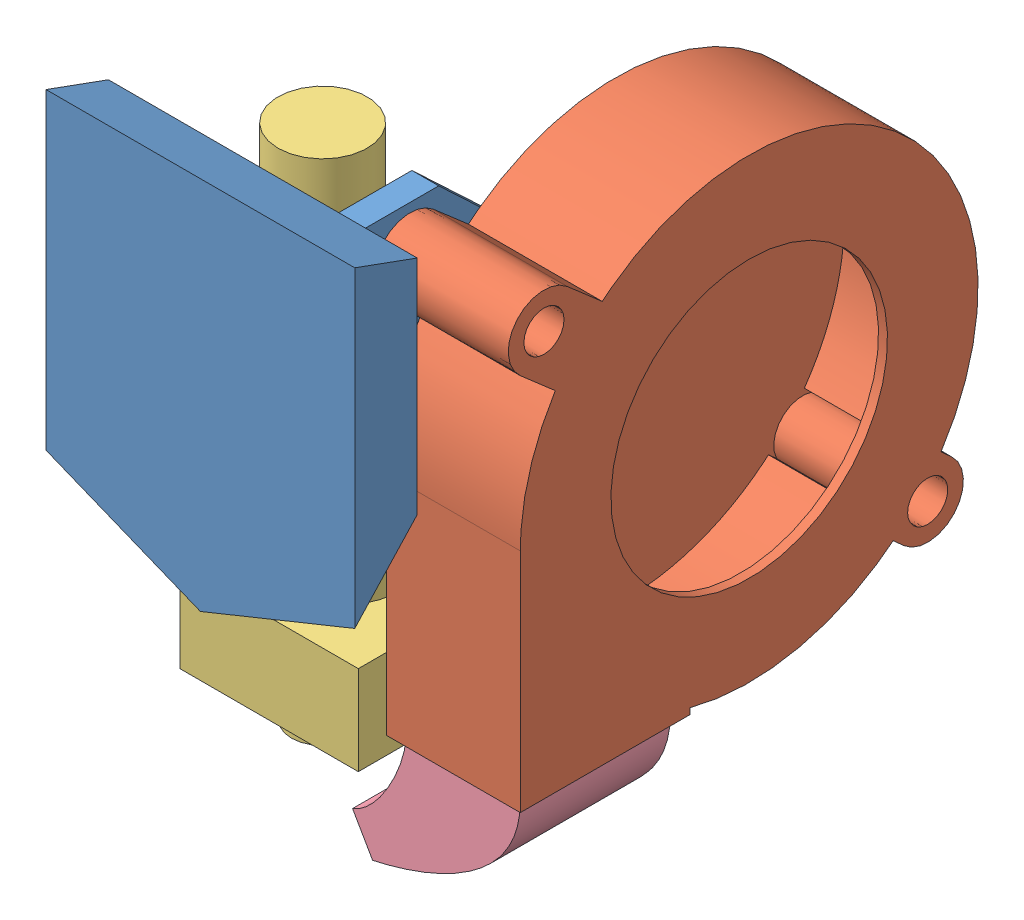
SolidWorks assembly Printer tool CR10, configuration Valor predeterminado. Lengths in mm.
Overall size (50 68.9 61).
4 component instances, 4 part files, 9 mates.
Components (placement in the parent):
- Printer_tool_CR10-1: Printer_tool_CR10 [Valor predeterminado] at (-2.4776 10.2101 60.4619) size (40.8 62.55 59)
- Cooler (50x50x15)-1: Cooler (50x50x15) [Valor predeterminado] at (9.0224 0.1623 25.4619) x (0 1 0) z (1 0 0) size (51.8 53 15)
- cr10_hotend-1: cr10_hotend [Valor predeterminado] at (-9.9776 -7.1878 39.2619) size (20 60 20.15)
- fan_duct-1: fan_duct [Valor predeterminado] at (16.5224 -10.2377 41.6119) x (0 0 -1) z (0 -1 0) size (36.4 19.53 29.42)
Mates (geometry in assembly coordinates):
- Concêntrico1: concentric aligned: cylinder of Printer_tool_CR10-1 through (9.0224 20.1623 48.4619) axis (-1 0 0) radius 2; cylinder of Cooler (50x50x15)-1 through (24.0224 20.1623 48.4619) axis (-1 0 0) radius 2.25
- Concêntrico2: concentric aligned: cylinder of Printer_tool_CR10-1 through (9.0224 -17.8377 5.4619) axis (-1 0 0) radius 2; cylinder of Cooler (50x50x15)-1 through (24.0224 -17.8377 5.4619) axis (-1 0 0) radius 2.25
- Coincidente1: coincident anti-aligned: plane of Printer_tool_CR10-1 through (9.0224 -17.8377 5.4619) normal (1 0 0); plane of Cooler (50x50x15)-1 through (9.0224 0.1623 25.4619) normal (-1 0 0)
- Concêntrico3: concentric aligned: cylinder of Printer_tool_CR10-1 through (-2.9776 2.8122 50.2619) axis (0 0 -1) radius 2; cylinder of cr10_hotend-1 through (-2.9776 2.8122 45.2619) axis (0 0 -1) radius 1.5
- Concêntrico4: concentric aligned: cylinder of Printer_tool_CR10-1 through (-16.9776 2.8122 50.2619) axis (0 0 -1) radius 2; cylinder of cr10_hotend-1 through (-16.9776 2.8122 45.2619) axis (0 0 -1) radius 1.5
- Coincidente2: coincident anti-aligned: plane of Printer_tool_CR10-1 through (-25.9776 -1.7899 45.2619) normal (0 0 -1); plane of cr10_hotend-1 through (-9.9776 -7.1878 45.2619) normal (0 0 1)
- Largura1: width aligned: plane of fan_duct-1 through (22.9224 -25.2377 50.0119) normal (0 0 1); plane of Cooler (50x50x15)-1 through (22.9224 -25.2377 33.2119) normal (0 0 -1); plane of fan_duct-1 through (24.0224 -25.2377 33.1119) normal (0 0 1); plane of Cooler (50x50x15)-1 through (24.0224 -25.2377 50.1119) normal (0 0 -1)
- Largura2: width aligned: plane of fan_duct-1 through (22.9224 -25.2377 50.0119) normal (1 0 0); plane of Cooler (50x50x15)-1 through (10.1224 -25.2377 50.0119) normal (-1 0 0); plane of fan_duct-1 through (10.0224 0.1623 25.4619) normal (1 0 0); plane of Cooler (50x50x15)-1 through (23.0224 0.1623 25.4619) normal (-1 0 0)
- Ranhura1: slot aligned: cylinder of Printer_tool_CR10-1 through (9.0224 -30.8377 20.4619) axis (-1 0 0) radius 2; plane of fan_duct-1 through (12.1224 -29.1877 22.6119) normal (0 -1 0); cylinder of fan_duct-1 through (12.1224 -30.8377 22.6119) axis (-1 0 0) radius 1.65
